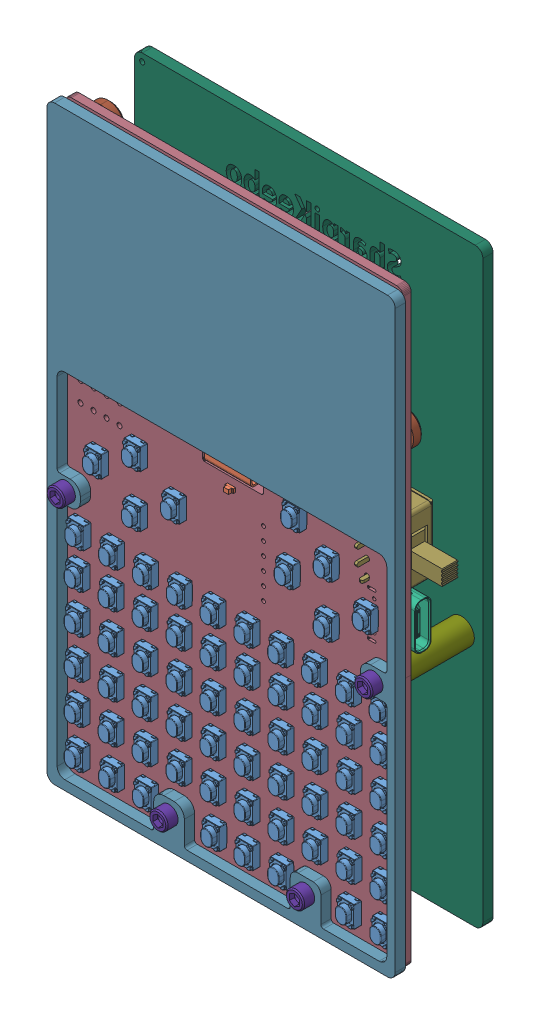
SolidWorks assembly boxingmars2024, configuration Défaut. Lengths in mm.
Overall size (72.24 115.41 21.31).
367 component instances, 20 part files, 1 mates.
Components (placement in the parent):
- pcbframe-1: pcbframe [Défaut] at (-188.8315 111.9596 -2.6) size (72.24 115.41 21.31)
  - pcbframe.STEP-1: pcbframe.STEP [Défaut] at origin size (71.24 115.32 9.7)
    - pcbframe.step.STEP-1: pcbframe.step.STEP [Défaut] at origin size (71.24 115.32 9.7)
      - SKRPABE010.step.STEP-1: SKRPABE010.step.STEP [Défaut] at (152.039 -127.29 1.65) x (0 1 0) z (1 0 0) size (4.6 2.5 3.2)
        - SOLID.step.STEP-1: SOLID.step.STEP [Défaut] at origin size (4.6 2.5 3.2)
      - SKRPABE010.step.STEP-2: SKRPABE010.step.STEP [Défaut] at (158.671 -127.29 1.65) x (0 1 0) z (1 0 0) size (4.6 2.5 3.2)
        - SOLID.step.STEP-1: SOLID.step.STEP [Défaut] at origin size (4.6 2.5 3.2)
      - SKRPABE010.step.STEP-3: SKRPABE010.step.STEP [Défaut] at (165.303 -127.29 1.65) x (0 1 0) z (1 0 0) size (4.6 2.5 3.2)
        - SOLID.step.STEP-1: SOLID.step.STEP [Défaut] at origin size (4.6 2.5 3.2)
      - SKRPABE010.step.STEP-4: SKRPABE010.step.STEP [Défaut] at (171.936 -127.29 1.65) x (0 1 0) z (1 0 0) size (4.6 2.5 3.2)
        - SOLID.step.STEP-1: SOLID.step.STEP [Défaut] at origin size (4.6 2.5 3.2)
      - SKRPABE010.step.STEP-5: SKRPABE010.step.STEP [Défaut] at (178.568 -127.29 1.65) x (0 1 0) z (1 0 0) size (4.6 2.5 3.2)
        - SOLID.step.STEP-1: SOLID.step.STEP [Défaut] at origin size (4.6 2.5 3.2)
      - SKRPABE010.step.STEP-6: SKRPABE010.step.STEP [Défaut] at (185.2 -127.29 1.65) x (0 1 0) z (1 0 0) size (4.6 2.5 3.2)
        - SOLID.step.STEP-1: SOLID.step.STEP [Défaut] at origin size (4.6 2.5 3.2)
      - SKRPABE010.step.STEP-7: SKRPABE010.step.STEP [Défaut] at (191.832 -127.29 1.65) x (0 1 0) z (1 0 0) size (4.6 2.5 3.2)
        - SOLID.step.STEP-1: SOLID.step.STEP [Défaut] at origin size (4.6 2.5 3.2)
      - SKRPABE010.step.STEP-8: SKRPABE010.step.STEP [Défaut] at (198.465 -127.29 1.65) x (0 1 0) z (1 0 0) size (4.6 2.5 3.2)
        - SOLID.step.STEP-1: SOLID.step.STEP [Défaut] at origin size (4.6 2.5 3.2)
      - SKRPABE010.step.STEP-9: SKRPABE010.step.STEP [Défaut] at (205.097 -127.29 1.65) x (0 1 0) z (1 0 0) size (4.6 2.5 3.2)
        - SOLID.step.STEP-1: SOLID.step.STEP [Défaut] at origin size (4.6 2.5 3.2)
      - SKRPABE010.step.STEP-10: SKRPABE010.step.STEP [Défaut] at (200.68 -101.255 1.65) x (0 1 0) z (1 0 0) size (4.6 2.5 3.2)
        - SOLID.step.STEP-1: SOLID.step.STEP [Défaut] at origin size (4.6 2.5 3.2)
      - SKRPABE010.step.STEP-11: SKRPABE010.step.STEP [Défaut] at (200.68 -111.415 1.65) x (0 1 0) z (1 0 0) size (4.6 2.5 3.2)
        - SOLID.step.STEP-1: SOLID.step.STEP [Défaut] at origin size (4.6 2.5 3.2)
      - SKRPABE010.step.STEP-12: SKRPABE010.step.STEP [Défaut] at (152.039 -134.91 1.65) x (0 1 0) z (1 0 0) size (4.6 2.5 3.2)
        - SOLID.step.STEP-1: SOLID.step.STEP [Défaut] at origin size (4.6 2.5 3.2)
      - SKRPABE010.step.STEP-13: SKRPABE010.step.STEP [Défaut] at (158.671 -134.91 1.65) x (0 1 0) z (1 0 0) size (4.6 2.5 3.2)
        - SOLID.step.STEP-1: SOLID.step.STEP [Défaut] at origin size (4.6 2.5 3.2)
      - SKRPABE010.step.STEP-14: SKRPABE010.step.STEP [Défaut] at (165.303 -134.91 1.65) x (0 1 0) z (1 0 0) size (4.6 2.5 3.2)
        - SOLID.step.STEP-1: SOLID.step.STEP [Défaut] at origin size (4.6 2.5 3.2)
      - SKRPABE010.step.STEP-15: SKRPABE010.step.STEP [Défaut] at (171.936 -134.91 1.65) x (0 1 0) z (1 0 0) size (4.6 2.5 3.2)
        - SOLID.step.STEP-1: SOLID.step.STEP [Défaut] at origin size (4.6 2.5 3.2)
      - SKRPABE010.step.STEP-16: SKRPABE010.step.STEP [Défaut] at (178.568 -134.91 1.65) x (0 1 0) z (1 0 0) size (4.6 2.5 3.2)
        - SOLID.step.STEP-1: SOLID.step.STEP [Défaut] at origin size (4.6 2.5 3.2)
      - SKRPABE010.step.STEP-17: SKRPABE010.step.STEP [Défaut] at (185.2 -134.91 1.65) x (0 1 0) z (1 0 0) size (4.6 2.5 3.2)
        - SOLID.step.STEP-1: SOLID.step.STEP [Défaut] at origin size (4.6 2.5 3.2)
      - SKRPABE010.step.STEP-18: SKRPABE010.step.STEP [Défaut] at (191.832 -134.91 1.65) x (0 1 0) z (1 0 0) size (4.6 2.5 3.2)
        - SOLID.step.STEP-1: SOLID.step.STEP [Défaut] at origin size (4.6 2.5 3.2)
      - SKRPABE010.step.STEP-19: SKRPABE010.step.STEP [Défaut] at (198.465 -134.91 1.65) x (0 1 0) z (1 0 0) size (4.6 2.5 3.2)
        - SOLID.step.STEP-1: SOLID.step.STEP [Défaut] at origin size (4.6 2.5 3.2)
      - SKRPABE010.step.STEP-20: SKRPABE010.step.STEP [Défaut] at (205.097 -134.91 1.65) x (0 1 0) z (1 0 0) size (4.6 2.5 3.2)
        - SOLID.step.STEP-1: SOLID.step.STEP [Défaut] at origin size (4.6 2.5 3.2)
      - SKRPABE010.step.STEP-21: SKRPABE010.step.STEP [Défaut] at (211.729 -134.91 1.65) x (0 1 0) z (1 0 0) size (4.6 2.5 3.2)
        - SOLID.step.STEP-1: SOLID.step.STEP [Défaut] at origin size (4.6 2.5 3.2)
      - SKRPABE010.step.STEP-22: SKRPABE010.step.STEP [Défaut] at (193.06 -106.335 1.65) x (0 1 0) z (1 0 0) size (4.6 2.5 3.2)
        - SOLID.step.STEP-1: SOLID.step.STEP [Défaut] at origin size (4.6 2.5 3.2)
      - SKRPABE010.step.STEP-23: SKRPABE010.step.STEP [Défaut] at (208.3 -106.335 1.65) x (0 1 0) z (1 0 0) size (4.6 2.5 3.2)
        - SOLID.step.STEP-1: SOLID.step.STEP [Défaut] at origin size (4.6 2.5 3.2)
      - SKRPABE010.step.STEP-24: SKRPABE010.step.STEP [Défaut] at (152.039 -142.53 1.65) x (0 1 0) z (1 0 0) size (4.6 2.5 3.2)
        - SOLID.step.STEP-1: SOLID.step.STEP [Défaut] at origin size (4.6 2.5 3.2)
      - SKRPABE010.step.STEP-25: SKRPABE010.step.STEP [Défaut] at (158.671 -142.53 1.65) x (0 1 0) z (1 0 0) size (4.6 2.5 3.2)
        - SOLID.step.STEP-1: SOLID.step.STEP [Défaut] at origin size (4.6 2.5 3.2)
      - SKRPABE010.step.STEP-26: SKRPABE010.step.STEP [Défaut] at (165.303 -142.53 1.65) x (0 1 0) z (1 0 0) size (4.6 2.5 3.2)
        - SOLID.step.STEP-1: SOLID.step.STEP [Défaut] at origin size (4.6 2.5 3.2)
      - SKRPABE010.step.STEP-27: SKRPABE010.step.STEP [Défaut] at (171.936 -142.53 1.65) x (0 1 0) z (1 0 0) size (4.6 2.5 3.2)
        - SOLID.step.STEP-1: SOLID.step.STEP [Défaut] at origin size (4.6 2.5 3.2)
      - SKRPABE010.step.STEP-28: SKRPABE010.step.STEP [Défaut] at (185.2 -142.53 1.65) x (0 1 0) z (1 0 0) size (4.6 2.5 3.2)
        - SOLID.step.STEP-1: SOLID.step.STEP [Défaut] at origin size (4.6 2.5 3.2)
      - SKRPABE010.step.STEP-29: SKRPABE010.step.STEP [Défaut] at (191.832 -142.53 1.65) x (0 1 0) z (1 0 0) size (4.6 2.5 3.2)
        - SOLID.step.STEP-1: SOLID.step.STEP [Défaut] at origin size (4.6 2.5 3.2)
      - SKRPABE010.step.STEP-30: SKRPABE010.step.STEP [Défaut] at (198.465 -142.53 1.65) x (0 1 0) z (1 0 0) size (4.6 2.5 3.2)
        - SOLID.step.STEP-1: SOLID.step.STEP [Défaut] at origin size (4.6 2.5 3.2)
      - SKRPABE010.step.STEP-31: SKRPABE010.step.STEP [Défaut] at (205.097 -142.53 1.65) x (0 1 0) z (1 0 0) size (4.6 2.5 3.2)
        - SOLID.step.STEP-1: SOLID.step.STEP [Défaut] at origin size (4.6 2.5 3.2)
      - SKRPABE010.step.STEP-32: SKRPABE010.step.STEP [Défaut] at (211.729 -142.53 1.65) x (0 1 0) z (1 0 0) size (4.6 2.5 3.2)
        - SOLID.step.STEP-1: SOLID.step.STEP [Défaut] at origin size (4.6 2.5 3.2)
      - SKRPABE010.step.STEP-33: SKRPABE010.step.STEP [Défaut] at (185.186 -120.178 1.65) x (0 1 0) z (1 0 0) size (4.6 2.5 3.2)
        - SOLID.step.STEP-1: SOLID.step.STEP [Défaut] at origin size (4.6 2.5 3.2)
      - SKRPABE010.step.STEP-34: SKRPABE010.step.STEP [Défaut] at (191.79 -120.178 1.65) x (0 1 0) z (1 0 0) size (4.6 2.5 3.2)
        - SOLID.step.STEP-1: SOLID.step.STEP [Défaut] at origin size (4.6 2.5 3.2)
      - SKRPABE010.step.STEP-35: SKRPABE010.step.STEP [Défaut] at (152.039 -150.15 1.65) x (0 1 0) z (1 0 0) size (4.6 2.5 3.2)
        - SOLID.step.STEP-1: SOLID.step.STEP [Défaut] at origin size (4.6 2.5 3.2)
      - SKRPABE010.step.STEP-36: SKRPABE010.step.STEP [Défaut] at (158.671 -150.15 1.65) x (0 1 0) z (1 0 0) size (4.6 2.5 3.2)
        - SOLID.step.STEP-1: SOLID.step.STEP [Défaut] at origin size (4.6 2.5 3.2)
      - SKRPABE010.step.STEP-37: SKRPABE010.step.STEP [Défaut] at (165.303 -150.15 1.65) x (0 1 0) z (1 0 0) size (4.6 2.5 3.2)
        - SOLID.step.STEP-1: SOLID.step.STEP [Défaut] at origin size (4.6 2.5 3.2)
      - SKRPABE010.step.STEP-38: SKRPABE010.step.STEP [Défaut] at (171.936 -150.15 1.65) x (0 1 0) z (1 0 0) size (4.6 2.5 3.2)
        - SOLID.step.STEP-1: SOLID.step.STEP [Défaut] at origin size (4.6 2.5 3.2)
      - SKRPABE010.step.STEP-39: SKRPABE010.step.STEP [Défaut] at (178.568 -150.15 1.65) x (0 1 0) z (1 0 0) size (4.6 2.5 3.2)
        - SOLID.step.STEP-1: SOLID.step.STEP [Défaut] at origin size (4.6 2.5 3.2)
      - SKRPABE010.step.STEP-40: SKRPABE010.step.STEP [Défaut] at (185.2 -150.15 1.65) x (0 1 0) z (1 0 0) size (4.6 2.5 3.2)
        - SOLID.step.STEP-1: SOLID.step.STEP [Défaut] at origin size (4.6 2.5 3.2)
      - SKRPABE010.step.STEP-41: SKRPABE010.step.STEP [Défaut] at (191.832 -150.15 1.65) x (0 1 0) z (1 0 0) size (4.6 2.5 3.2)
        - SOLID.step.STEP-1: SOLID.step.STEP [Défaut] at origin size (4.6 2.5 3.2)
      - SKRPABE010.step.STEP-42: SKRPABE010.step.STEP [Défaut] at (198.465 -150.15 1.65) x (0 1 0) z (1 0 0) size (4.6 2.5 3.2)
        - SOLID.step.STEP-1: SOLID.step.STEP [Défaut] at origin size (4.6 2.5 3.2)
      - SKRPABE010.step.STEP-43: SKRPABE010.step.STEP [Défaut] at (205.097 -150.15 1.65) x (0 1 0) z (1 0 0) size (4.6 2.5 3.2)
        - SOLID.step.STEP-1: SOLID.step.STEP [Défaut] at origin size (4.6 2.5 3.2)
      - SKRPABE010.step.STEP-44: SKRPABE010.step.STEP [Défaut] at (211.729 -150.15 1.65) x (0 1 0) z (1 0 0) size (4.6 2.5 3.2)
        - SOLID.step.STEP-1: SOLID.step.STEP [Défaut] at origin size (4.6 2.5 3.2)
      - SKRPABE010.step.STEP-45: SKRPABE010.step.STEP [Défaut] at (198.394 -120.178 1.65) x (0 1 0) z (1 0 0) size (4.6 2.5 3.2)
        - SOLID.step.STEP-1: SOLID.step.STEP [Défaut] at origin size (4.6 2.5 3.2)
      - SKRPABE010.step.STEP-46: SKRPABE010.step.STEP [Défaut] at (204.998 -120.178 1.65) x (0 1 0) z (1 0 0) size (4.6 2.5 3.2)
        - SOLID.step.STEP-1: SOLID.step.STEP [Défaut] at origin size (4.6 2.5 3.2)
      - SKRPABE010.step.STEP-47: SKRPABE010.step.STEP [Défaut] at (152.039 -157.77 1.65) x (0 1 0) z (1 0 0) size (4.6 2.5 3.2)
        - SOLID.step.STEP-1: SOLID.step.STEP [Défaut] at origin size (4.6 2.5 3.2)
      - SKRPABE010.step.STEP-48: SKRPABE010.step.STEP [Défaut] at (158.77 -157.77 1.65) x (0 1 0) z (1 0 0) size (4.6 2.5 3.2)
        - SOLID.step.STEP-1: SOLID.step.STEP [Défaut] at origin size (4.6 2.5 3.2)
      - SKRPABE010.step.STEP-49: SKRPABE010.step.STEP [Défaut] at (165.374 -157.77 1.65) x (0 1 0) z (1 0 0) size (4.6 2.5 3.2)
        - SOLID.step.STEP-1: SOLID.step.STEP [Défaut] at origin size (4.6 2.5 3.2)
      - SKRPABE010.step.STEP-50: SKRPABE010.step.STEP [Défaut] at (178.709 -157.77 1.65) x (0 1 0) z (1 0 0) size (4.6 2.5 3.2)
        - SOLID.step.STEP-1: SOLID.step.STEP [Défaut] at origin size (4.6 2.5 3.2)
      - SKRPABE010.step.STEP-51: SKRPABE010.step.STEP [Défaut] at (185.186 -157.77 1.65) x (0 1 0) z (1 0 0) size (4.6 2.5 3.2)
        - SOLID.step.STEP-1: SOLID.step.STEP [Défaut] at origin size (4.6 2.5 3.2)
      - SKRPABE010.step.STEP-52: SKRPABE010.step.STEP [Défaut] at (191.79 -157.77 1.65) x (0 1 0) z (1 0 0) size (4.6 2.5 3.2)
        - SOLID.step.STEP-1: SOLID.step.STEP [Défaut] at origin size (4.6 2.5 3.2)
      - SKRPABE010.step.STEP-53: SKRPABE010.step.STEP [Défaut] at (211.729 -157.77 1.65) x (0 1 0) z (1 0 0) size (4.6 2.5 3.2)
        - SOLID.step.STEP-1: SOLID.step.STEP [Défaut] at origin size (4.6 2.5 3.2)
      - SKRPABE010.step.STEP-54: SKRPABE010.step.STEP [Défaut] at (211.602 -120.178 1.65) x (0 1 0) z (1 0 0) size (4.6 2.5 3.2)
        - SOLID.step.STEP-1: SOLID.step.STEP [Défaut] at origin size (4.6 2.5 3.2)
      - SKRPABE010.step.STEP-55: SKRPABE010.step.STEP [Défaut] at (152.166 -120.178 1.65) x (0 1 0) z (1 0 0) size (4.6 2.5 3.2)
        - SOLID.step.STEP-1: SOLID.step.STEP [Défaut] at origin size (4.6 2.5 3.2)
      - SKRPABE010.step.STEP-56: SKRPABE010.step.STEP [Défaut] at (158.77 -120.178 1.65) x (0 1 0) z (1 0 0) size (4.6 2.5 3.2)
        - SOLID.step.STEP-1: SOLID.step.STEP [Défaut] at origin size (4.6 2.5 3.2)
      - SKRPABE010.step.STEP-57: SKRPABE010.step.STEP [Défaut] at (165.374 -120.178 1.65) x (0 1 0) z (1 0 0) size (4.6 2.5 3.2)
        - SOLID.step.STEP-1: SOLID.step.STEP [Défaut] at origin size (4.6 2.5 3.2)
      - SKRPABE010.step.STEP-58: SKRPABE010.step.STEP [Défaut] at (171.978 -120.178 1.65) x (0 1 0) z (1 0 0) size (4.6 2.5 3.2)
        - SOLID.step.STEP-1: SOLID.step.STEP [Défaut] at origin size (4.6 2.5 3.2)
      - SKRPABE010.step.STEP-59: SKRPABE010.step.STEP [Défaut] at (178.582 -120.178 1.65) x (0 1 0) z (1 0 0) size (4.6 2.5 3.2)
        - SOLID.step.STEP-1: SOLID.step.STEP [Défaut] at origin size (4.6 2.5 3.2)
      - SKRPABE010.step.STEP-60: SKRPABE010.step.STEP [Défaut] at (211.729 -127.29 1.65) x (0 1 0) z (1 0 0) size (4.6 2.5 3.2)
        - SOLID.step.STEP-1: SOLID.step.STEP [Défaut] at origin size (4.6 2.5 3.2)
      - SKRPABE010.step.STEP-61: SKRPABE010.step.STEP [Défaut] at (204.998 -157.77 1.65) x (0 1 0) z (1 0 0) size (4.6 2.5 3.2)
        - SOLID.step.STEP-1: SOLID.step.STEP [Défaut] at origin size (4.6 2.5 3.2)
      - SKRPABE010.step.STEP-62: SKRPABE010.step.STEP [Défaut] at (178.568 -142.53 1.65) x (0 1 0) z (1 0 0) size (4.6 2.5 3.2)
        - SOLID.step.STEP-1: SOLID.step.STEP [Défaut] at origin size (4.6 2.5 3.2)
      - SKRPABE010.step.STEP-63: SKRPABE010.step.STEP [Défaut] at (194.33 -96.048 1.65) x (0 1 0) z (1 0 0) size (4.6 2.5 3.2)
        - SOLID.step.STEP-1: SOLID.step.STEP [Défaut] at origin size (4.6 2.5 3.2)
      - SKRPABE010.step.STEP-64: SKRPABE010.step.STEP [Défaut] at (155.595 -106.335 1.65) x (0 1 0) z (1 0 0) size (4.6 2.5 3.2)
        - SOLID.step.STEP-1: SOLID.step.STEP [Défaut] at origin size (4.6 2.5 3.2)
      - SKRPABE010.step.STEP-65: SKRPABE010.step.STEP [Défaut] at (163.215 -111.415 1.65) x (0 1 0) z (1 0 0) size (4.6 2.5 3.2)
        - SOLID.step.STEP-1: SOLID.step.STEP [Défaut] at origin size (4.6 2.5 3.2)
      - SKRPABE010.step.STEP-66: SKRPABE010.step.STEP [Défaut] at (163.215 -101.255 1.65) x (0 1 0) z (1 0 0) size (4.6 2.5 3.2)
        - SOLID.step.STEP-1: SOLID.step.STEP [Défaut] at origin size (4.6 2.5 3.2)
      - SKRPABE010.step.STEP-67: SKRPABE010.step.STEP [Défaut] at (170.835 -106.335 1.65) x (0 1 0) z (1 0 0) size (4.6 2.5 3.2)
        - SOLID.step.STEP-1: SOLID.step.STEP [Défaut] at origin size (4.6 2.5 3.2)
      - LED_0603_1608Metric.step.STEP-1: LED_0603_1608Metric.step.STEP [Défaut] at (181.204 -98.4885 1.65) size (1.6 0.8 1.1)
        - SOLID-0.step.STEP-1: SOLID-0.step.STEP [Défaut] at origin size (1.6 0.8 1.1)
      - C_0603_1608Metric.step.STEP-1: C_0603_1608Metric.step.STEP [Défaut] at (185.42 -81.915 -0.05) x (0 1 0) z (0 0 -1) size (1.6 0.8 0.8)
        - SOLID-1.step.STEP-1: SOLID-1.step.STEP [Défaut] at origin size (1.6 0.8 0.8)
      - C_0603_1608Metric.step.STEP-2: C_0603_1608Metric.step.STEP [Défaut] at (181.61 -81.915 -0.05) x (0 1 0) z (0 0 -1) size (1.6 0.8 0.8)
        - SOLID-1.step.STEP-1: SOLID-1.step.STEP [Défaut] at origin size (1.6 0.8 0.8)
      - C_0603_1608Metric.step.STEP-3: C_0603_1608Metric.step.STEP [Défaut] at (179.705 -81.915 -0.05) x (0 1 0) z (0 0 -1) size (1.6 0.8 0.8)
        - SOLID-1.step.STEP-1: SOLID-1.step.STEP [Défaut] at origin size (1.6 0.8 0.8)
      - R_0603_1608Metric.step.STEP-1: R_0603_1608Metric.step.STEP [Défaut] at (199.39 -97.7265 -0.05) x (1 0 0) z (0 0 -1) size (1.6 0.8 0.45)
        - SOLID-2.step.STEP-1: SOLID-2.step.STEP [Défaut] at origin size (1.6 0.8 0.45)
      - R_0603_1608Metric.step.STEP-2: R_0603_1608Metric.step.STEP [Défaut] at (195.136 -106.236 -0.05) x (-1 0 0) z (0 0 -1) size (1.6 0.8 0.45)
        - SOLID-2.step.STEP-1: SOLID-2.step.STEP [Défaut] at origin size (1.6 0.8 0.45)
      - R_0603_1608Metric.step.STEP-3: R_0603_1608Metric.step.STEP [Défaut] at (170.284 -95.885 -0.05) x (1 0 0) z (0 0 -1) size (1.6 0.8 0.45)
        - SOLID-2.step.STEP-1: SOLID-2.step.STEP [Défaut] at origin size (1.6 0.8 0.45)
      - R_0603_1608Metric.step.STEP-4: R_0603_1608Metric.step.STEP [Défaut] at (152.34 -106.331 -0.05) x (-1 0 0) z (0 0 -1) size (1.6 0.8 0.45)
        - SOLID-2.step.STEP-1: SOLID-2.step.STEP [Défaut] at origin size (1.6 0.8 0.45)
      - R_0603_1608Metric.step.STEP-5: R_0603_1608Metric.step.STEP [Défaut] at (156.976 -112.872 -0.05) x (-1 0 0) z (0 0 -1) size (1.6 0.8 0.45)
        - SOLID-2.step.STEP-1: SOLID-2.step.STEP [Défaut] at origin size (1.6 0.8 0.45)
      - R_0603_1608Metric.step.STEP-6: R_0603_1608Metric.step.STEP [Défaut] at (156.865 -109.696 -0.05) x (-1 0 0) z (0 0 -1) size (1.6 0.8 0.45)
        - SOLID-2.step.STEP-1: SOLID-2.step.STEP [Défaut] at origin size (1.6 0.8 0.45)
      - R_0603_1608Metric.step.STEP-7: R_0603_1608Metric.step.STEP [Défaut] at (170.18 -93.98 -0.05) x (1 0 0) z (0 0 -1) size (1.6 0.8 0.45)
        - SOLID-2.step.STEP-1: SOLID-2.step.STEP [Défaut] at origin size (1.6 0.8 0.45)
      - R_0603_1608Metric.step.STEP-8: R_0603_1608Metric.step.STEP [Défaut] at (152.467 -103.283 -0.05) x (-1 0 0) z (0 0 -1) size (1.6 0.8 0.45)
        - SOLID-2.step.STEP-1: SOLID-2.step.STEP [Défaut] at origin size (1.6 0.8 0.45)
      - R_0603_1608Metric.step.STEP-9: R_0603_1608Metric.step.STEP [Défaut] at (156.722 -106.268 -0.05) x (-1 0 0) z (0 0 -1) size (1.6 0.8 0.45)
        - SOLID-2.step.STEP-1: SOLID-2.step.STEP [Défaut] at origin size (1.6 0.8 0.45)
      - R_0603_1608Metric.step.STEP-10: R_0603_1608Metric.step.STEP [Défaut] at (156.785 -103.283 -0.05) x (-1 0 0) z (0 0 -1) size (1.6 0.8 0.45)
        - SOLID-2.step.STEP-1: SOLID-2.step.STEP [Défaut] at origin size (1.6 0.8 0.45)
      - C_0603_1608Metric.step.STEP-4: C_0603_1608Metric.step.STEP [Défaut] at (174.219 -51.1556 -0.05) x (0 1 0) z (0 0 -1) size (1.6 0.8 0.8)
        - SOLID-1.step.STEP-1: SOLID-1.step.STEP [Défaut] at origin size (1.6 0.8 0.8)
      - C_0603_1608Metric.step.STEP-5: C_0603_1608Metric.step.STEP [Défaut] at (177.775 -51.1686 -0.05) x (0 1 0) z (0 0 -1) size (1.6 0.8 0.8)
        - SOLID-1.step.STEP-1: SOLID-1.step.STEP [Défaut] at origin size (1.6 0.8 0.8)
      - C_0603_1608Metric.step.STEP-6: C_0603_1608Metric.step.STEP [Défaut] at (152.756 -66.9544 -0.05) x (0 1 0) z (0 0 -1) size (1.6 0.8 0.8)
        - SOLID-1.step.STEP-1: SOLID-1.step.STEP [Défaut] at origin size (1.6 0.8 0.8)
      - C_0603_1608Metric.step.STEP-7: C_0603_1608Metric.step.STEP [Défaut] at (172.441 -51.1686 -0.05) x (0 1 0) z (0 0 -1) size (1.6 0.8 0.8)
        - SOLID-1.step.STEP-1: SOLID-1.step.STEP [Défaut] at origin size (1.6 0.8 0.8)
      - C_0603_1608Metric.step.STEP-8: C_0603_1608Metric.step.STEP [Défaut] at (175.997 -51.1686 -0.05) x (0 1 0) z (0 0 -1) size (1.6 0.8 0.8)
        - SOLID-1.step.STEP-1: SOLID-1.step.STEP [Défaut] at origin size (1.6 0.8 0.8)
      - D_SOD-323.step.STEP-1: D_SOD-323.step.STEP [Défaut] at (151.892 -127.254 -0.05) x (0 -1 0) z (0 0 -1) size (2.5 1.25 1.1)
        - SOLID-3.step.STEP-1: SOLID-3.step.STEP [Défaut] at origin size (2.5 1.25 1.1)
      - D_SOD-323.step.STEP-2: D_SOD-323.step.STEP [Défaut] at (158.496 -127.254 -0.05) x (0 -1 0) z (0 0 -1) size (2.5 1.25 1.1)
        - SOLID-3.step.STEP-1: SOLID-3.step.STEP [Défaut] at origin size (2.5 1.25 1.1)
      - D_SOD-323.step.STEP-3: D_SOD-323.step.STEP [Défaut] at (165.1 -127.254 -0.05) x (0 -1 0) z (0 0 -1) size (2.5 1.25 1.1)
        - SOLID-3.step.STEP-1: SOLID-3.step.STEP [Défaut] at origin size (2.5 1.25 1.1)
      - D_SOD-323.step.STEP-4: D_SOD-323.step.STEP [Défaut] at (171.704 -127.254 -0.05) x (0 -1 0) z (0 0 -1) size (2.5 1.25 1.1)
        - SOLID-3.step.STEP-1: SOLID-3.step.STEP [Défaut] at origin size (2.5 1.25 1.1)
      - D_SOD-323.step.STEP-5: D_SOD-323.step.STEP [Défaut] at (178.308 -127.254 -0.05) x (0 -1 0) z (0 0 -1) size (2.5 1.25 1.1)
        - SOLID-3.step.STEP-1: SOLID-3.step.STEP [Défaut] at origin size (2.5 1.25 1.1)
      - D_SOD-323.step.STEP-6: D_SOD-323.step.STEP [Défaut] at (185.166 -127.254 -0.05) x (0 -1 0) z (0 0 -1) size (2.5 1.25 1.1)
        - SOLID-3.step.STEP-1: SOLID-3.step.STEP [Défaut] at origin size (2.5 1.25 1.1)
      - D_SOD-323.step.STEP-7: D_SOD-323.step.STEP [Défaut] at (191.77 -127.254 -0.05) x (0 -1 0) z (0 0 -1) size (2.5 1.25 1.1)
        - SOLID-3.step.STEP-1: SOLID-3.step.STEP [Défaut] at origin size (2.5 1.25 1.1)
      - D_SOD-323.step.STEP-8: D_SOD-323.step.STEP [Défaut] at (198.374 -127.254 -0.05) x (0 -1 0) z (0 0 -1) size (2.5 1.25 1.1)
        - SOLID-3.step.STEP-1: SOLID-3.step.STEP [Défaut] at origin size (2.5 1.25 1.1)
      - D_SOD-323.step.STEP-9: D_SOD-323.step.STEP [Défaut] at (204.978 -127.254 -0.05) x (0 -1 0) z (0 0 -1) size (2.5 1.25 1.1)
        - SOLID-3.step.STEP-1: SOLID-3.step.STEP [Défaut] at origin size (2.5 1.25 1.1)
      - D_SOD-323.step.STEP-10: D_SOD-323.step.STEP [Défaut] at (211.582 -127.274 -0.05) x (0 -1 0) z (0 0 -1) size (2.5 1.25 1.1)
        - SOLID-3.step.STEP-1: SOLID-3.step.STEP [Défaut] at origin size (2.5 1.25 1.1)
      - D_SOD-323.step.STEP-11: D_SOD-323.step.STEP [Défaut] at (206.946 -114.18 -0.05) x (0 -1 0) z (0 0 -1) size (2.5 1.25 1.1)
        - SOLID-3.step.STEP-1: SOLID-3.step.STEP [Défaut] at origin size (2.5 1.25 1.1)
      - D_SOD-323.step.STEP-12: D_SOD-323.step.STEP [Défaut] at (202.374 -114.216 -0.05) x (0 -1 0) z (0 0 -1) size (2.5 1.25 1.1)
        - SOLID-3.step.STEP-1: SOLID-3.step.STEP [Défaut] at origin size (2.5 1.25 1.1)
      - D_SOD-323.step.STEP-13: D_SOD-323.step.STEP [Défaut] at (151.892 -134.874 -0.05) x (0 -1 0) z (0 0 -1) size (2.5 1.25 1.1)
        - SOLID-3.step.STEP-1: SOLID-3.step.STEP [Défaut] at origin size (2.5 1.25 1.1)
      - D_SOD-323.step.STEP-14: D_SOD-323.step.STEP [Défaut] at (158.496 -134.874 -0.05) x (0 -1 0) z (0 0 -1) size (2.5 1.25 1.1)
        - SOLID-3.step.STEP-1: SOLID-3.step.STEP [Défaut] at origin size (2.5 1.25 1.1)
      - D_SOD-323.step.STEP-15: D_SOD-323.step.STEP [Défaut] at (165.1 -134.874 -0.05) x (0 -1 0) z (0 0 -1) size (2.5 1.25 1.1)
        - SOLID-3.step.STEP-1: SOLID-3.step.STEP [Défaut] at origin size (2.5 1.25 1.1)
      - D_SOD-323.step.STEP-16: D_SOD-323.step.STEP [Défaut] at (171.704 -134.874 -0.05) x (0 -1 0) z (0 0 -1) size (2.5 1.25 1.1)
        - SOLID-3.step.STEP-1: SOLID-3.step.STEP [Défaut] at origin size (2.5 1.25 1.1)
      - D_SOD-323.step.STEP-17: D_SOD-323.step.STEP [Défaut] at (178.562 -134.874 -0.05) x (0 -1 0) z (0 0 -1) size (2.5 1.25 1.1)
        - SOLID-3.step.STEP-1: SOLID-3.step.STEP [Défaut] at origin size (2.5 1.25 1.1)
      - D_SOD-323.step.STEP-18: D_SOD-323.step.STEP [Défaut] at (185.166 -134.874 -0.05) x (0 -1 0) z (0 0 -1) size (2.5 1.25 1.1)
        - SOLID-3.step.STEP-1: SOLID-3.step.STEP [Défaut] at origin size (2.5 1.25 1.1)
      - D_SOD-323.step.STEP-19: D_SOD-323.step.STEP [Défaut] at (191.516 -134.874 -0.05) x (0 -1 0) z (0 0 -1) size (2.5 1.25 1.1)
        - SOLID-3.step.STEP-1: SOLID-3.step.STEP [Défaut] at origin size (2.5 1.25 1.1)
      - D_SOD-323.step.STEP-20: D_SOD-323.step.STEP [Défaut] at (198.374 -134.874 -0.05) x (0 -1 0) z (0 0 -1) size (2.5 1.25 1.1)
        - SOLID-3.step.STEP-1: SOLID-3.step.STEP [Défaut] at origin size (2.5 1.25 1.1)
      - D_SOD-323.step.STEP-21: D_SOD-323.step.STEP [Défaut] at (204.978 -134.874 -0.05) x (0 -1 0) z (0 0 -1) size (2.5 1.25 1.1)
        - SOLID-3.step.STEP-1: SOLID-3.step.STEP [Défaut] at origin size (2.5 1.25 1.1)
      - D_SOD-323.step.STEP-22: D_SOD-323.step.STEP [Défaut] at (211.582 -134.874 -0.05) x (0 -1 0) z (0 0 -1) size (2.5 1.25 1.1)
        - SOLID-3.step.STEP-1: SOLID-3.step.STEP [Défaut] at origin size (2.5 1.25 1.1)
      - D_SOD-323.step.STEP-23: D_SOD-323.step.STEP [Défaut] at (197.866 -114.18 -0.05) x (0 -1 0) z (0 0 -1) size (2.5 1.25 1.1)
        - SOLID-3.step.STEP-1: SOLID-3.step.STEP [Défaut] at origin size (2.5 1.25 1.1)
      - D_SOD-323.step.STEP-24: D_SOD-323.step.STEP [Défaut] at (192.024 -114.18 -0.05) x (0 -1 0) z (0 0 -1) size (2.5 1.25 1.1)
        - SOLID-3.step.STEP-1: SOLID-3.step.STEP [Défaut] at origin size (2.5 1.25 1.1)
      - D_SOD-323.step.STEP-25: D_SOD-323.step.STEP [Défaut] at (151.892 -142.494 -0.05) x (0 -1 0) z (0 0 -1) size (2.5 1.25 1.1)
        - SOLID-3.step.STEP-1: SOLID-3.step.STEP [Défaut] at origin size (2.5 1.25 1.1)
      - D_SOD-323.step.STEP-26: D_SOD-323.step.STEP [Défaut] at (158.496 -142.494 -0.05) x (0 -1 0) z (0 0 -1) size (2.5 1.25 1.1)
        - SOLID-3.step.STEP-1: SOLID-3.step.STEP [Défaut] at origin size (2.5 1.25 1.1)
      - D_SOD-323.step.STEP-27: D_SOD-323.step.STEP [Défaut] at (165.1 -142.494 -0.05) x (0 -1 0) z (0 0 -1) size (2.5 1.25 1.1)
        - SOLID-3.step.STEP-1: SOLID-3.step.STEP [Défaut] at origin size (2.5 1.25 1.1)
      - D_SOD-323.step.STEP-28: D_SOD-323.step.STEP [Défaut] at (171.704 -142.494 -0.05) x (0 -1 0) z (0 0 -1) size (2.5 1.25 1.1)
        - SOLID-3.step.STEP-1: SOLID-3.step.STEP [Défaut] at origin size (2.5 1.25 1.1)
      - D_SOD-323.step.STEP-29: D_SOD-323.step.STEP [Défaut] at (178.562 -142.494 -0.05) x (0 -1 0) z (0 0 -1) size (2.5 1.25 1.1)
        - SOLID-3.step.STEP-1: SOLID-3.step.STEP [Défaut] at origin size (2.5 1.25 1.1)
      - D_SOD-323.step.STEP-30: D_SOD-323.step.STEP [Défaut] at (184.912 -142.494 -0.05) x (0 -1 0) z (0 0 -1) size (2.5 1.25 1.1)
        - SOLID-3.step.STEP-1: SOLID-3.step.STEP [Défaut] at origin size (2.5 1.25 1.1)
      - D_SOD-323.step.STEP-31: D_SOD-323.step.STEP [Défaut] at (191.77 -142.494 -0.05) x (0 -1 0) z (0 0 -1) size (2.5 1.25 1.1)
        - SOLID-3.step.STEP-1: SOLID-3.step.STEP [Défaut] at origin size (2.5 1.25 1.1)
      - D_SOD-323.step.STEP-32: D_SOD-323.step.STEP [Défaut] at (198.12 -142.494 -0.05) x (0 -1 0) z (0 0 -1) size (2.5 1.25 1.1)
        - SOLID-3.step.STEP-1: SOLID-3.step.STEP [Défaut] at origin size (2.5 1.25 1.1)
      - D_SOD-323.step.STEP-33: D_SOD-323.step.STEP [Défaut] at (204.978 -142.494 -0.05) x (0 -1 0) z (0 0 -1) size (2.5 1.25 1.1)
        - SOLID-3.step.STEP-1: SOLID-3.step.STEP [Défaut] at origin size (2.5 1.25 1.1)
      - D_SOD-323.step.STEP-34: D_SOD-323.step.STEP [Défaut] at (211.582 -142.494 -0.05) x (0 -1 0) z (0 0 -1) size (2.5 1.25 1.1)
        - SOLID-3.step.STEP-1: SOLID-3.step.STEP [Défaut] at origin size (2.5 1.25 1.1)
      - D_SOD-323.step.STEP-35: D_SOD-323.step.STEP [Défaut] at (185.166 -120.142 -0.05) x (0 -1 0) z (0 0 -1) size (2.5 1.25 1.1)
        - SOLID-3.step.STEP-1: SOLID-3.step.STEP [Défaut] at origin size (2.5 1.25 1.1)
      - D_SOD-323.step.STEP-36: D_SOD-323.step.STEP [Défaut] at (191.77 -120.142 -0.05) x (0 -1 0) z (0 0 -1) size (2.5 1.25 1.1)
        - SOLID-3.step.STEP-1: SOLID-3.step.STEP [Défaut] at origin size (2.5 1.25 1.1)
      - D_SOD-323.step.STEP-37: D_SOD-323.step.STEP [Défaut] at (151.892 -150.114 -0.05) x (0 -1 0) z (0 0 -1) size (2.5 1.25 1.1)
        - SOLID-3.step.STEP-1: SOLID-3.step.STEP [Défaut] at origin size (2.5 1.25 1.1)
      - D_SOD-323.step.STEP-38: D_SOD-323.step.STEP [Défaut] at (158.75 -150.114 -0.05) x (0 -1 0) z (0 0 -1) size (2.5 1.25 1.1)
        - SOLID-3.step.STEP-1: SOLID-3.step.STEP [Défaut] at origin size (2.5 1.25 1.1)
      - D_SOD-323.step.STEP-39: D_SOD-323.step.STEP [Défaut] at (165.1 -150.114 -0.05) x (0 -1 0) z (0 0 -1) size (2.5 1.25 1.1)
        - SOLID-3.step.STEP-1: SOLID-3.step.STEP [Défaut] at origin size (2.5 1.25 1.1)
      - D_SOD-323.step.STEP-40: D_SOD-323.step.STEP [Défaut] at (171.958 -150.114 -0.05) x (0 -1 0) z (0 0 -1) size (2.5 1.25 1.1)
        - SOLID-3.step.STEP-1: SOLID-3.step.STEP [Défaut] at origin size (2.5 1.25 1.1)
      - D_SOD-323.step.STEP-41: D_SOD-323.step.STEP [Défaut] at (178.308 -150.114 -0.05) x (0 -1 0) z (0 0 -1) size (2.5 1.25 1.1)
        - SOLID-3.step.STEP-1: SOLID-3.step.STEP [Défaut] at origin size (2.5 1.25 1.1)
      - D_SOD-323.step.STEP-42: D_SOD-323.step.STEP [Défaut] at (185.166 -150.114 -0.05) x (0 -1 0) z (0 0 -1) size (2.5 1.25 1.1)
        - SOLID-3.step.STEP-1: SOLID-3.step.STEP [Défaut] at origin size (2.5 1.25 1.1)
      - D_SOD-323.step.STEP-43: D_SOD-323.step.STEP [Défaut] at (191.77 -150.114 -0.05) x (0 -1 0) z (0 0 -1) size (2.5 1.25 1.1)
        - SOLID-3.step.STEP-1: SOLID-3.step.STEP [Défaut] at origin size (2.5 1.25 1.1)
      - D_SOD-323.step.STEP-44: D_SOD-323.step.STEP [Défaut] at (198.374 -150.114 -0.05) x (0 -1 0) z (0 0 -1) size (2.5 1.25 1.1)
        - SOLID-3.step.STEP-1: SOLID-3.step.STEP [Défaut] at origin size (2.5 1.25 1.1)
      - D_SOD-323.step.STEP-45: D_SOD-323.step.STEP [Défaut] at (204.978 -150.114 -0.05) x (0 -1 0) z (0 0 -1) size (2.5 1.25 1.1)
        - SOLID-3.step.STEP-1: SOLID-3.step.STEP [Défaut] at origin size (2.5 1.25 1.1)
      - D_SOD-323.step.STEP-46: D_SOD-323.step.STEP [Défaut] at (211.836 -150.114 -0.05) x (0 -1 0) z (0 0 -1) size (2.5 1.25 1.1)
        - SOLID-3.step.STEP-1: SOLID-3.step.STEP [Défaut] at origin size (2.5 1.25 1.1)
      - D_SOD-323.step.STEP-47: D_SOD-323.step.STEP [Défaut] at (198.374 -120.142 -0.05) x (0 -1 0) z (0 0 -1) size (2.5 1.25 1.1)
        - SOLID-3.step.STEP-1: SOLID-3.step.STEP [Défaut] at origin size (2.5 1.25 1.1)
      - D_SOD-323.step.STEP-48: D_SOD-323.step.STEP [Défaut] at (204.978 -120.142 -0.05) x (0 -1 0) z (0 0 -1) size (2.5 1.25 1.1)
        - SOLID-3.step.STEP-1: SOLID-3.step.STEP [Défaut] at origin size (2.5 1.25 1.1)
      - D_SOD-323.step.STEP-49: D_SOD-323.step.STEP [Défaut] at (151.892 -157.734 -0.05) x (0 -1 0) z (0 0 -1) size (2.5 1.25 1.1)
        - SOLID-3.step.STEP-1: SOLID-3.step.STEP [Défaut] at origin size (2.5 1.25 1.1)
      - D_SOD-323.step.STEP-50: D_SOD-323.step.STEP [Défaut] at (158.75 -157.734 -0.05) x (0 -1 0) z (0 0 -1) size (2.5 1.25 1.1)
        - SOLID-3.step.STEP-1: SOLID-3.step.STEP [Défaut] at origin size (2.5 1.25 1.1)
      - D_SOD-323.step.STEP-51: D_SOD-323.step.STEP [Défaut] at (165.1 -157.734 -0.05) x (0 -1 0) z (0 0 -1) size (2.5 1.25 1.1)
        - SOLID-3.step.STEP-1: SOLID-3.step.STEP [Défaut] at origin size (2.5 1.25 1.1)
      - D_SOD-323.step.STEP-52: D_SOD-323.step.STEP [Défaut] at (178.562 -157.734 -0.05) x (0 -1 0) z (0 0 -1) size (2.5 1.25 1.1)
        - SOLID-3.step.STEP-1: SOLID-3.step.STEP [Défaut] at origin size (2.5 1.25 1.1)
      - D_SOD-323.step.STEP-53: D_SOD-323.step.STEP [Défaut] at (204.978 -157.734 -0.05) x (0 -1 0) z (0 0 -1) size (2.5 1.25 1.1)
        - SOLID-3.step.STEP-1: SOLID-3.step.STEP [Défaut] at origin size (2.5 1.25 1.1)
      - D_SOD-323.step.STEP-54: D_SOD-323.step.STEP [Défaut] at (211.582 -157.734 -0.05) x (0 -1 0) z (0 0 -1) size (2.5 1.25 1.1)
        - SOLID-3.step.STEP-1: SOLID-3.step.STEP [Défaut] at origin size (2.5 1.25 1.1)
      - D_SOD-323.step.STEP-55: D_SOD-323.step.STEP [Défaut] at (211.582 -120.142 -0.05) x (0 -1 0) z (0 0 -1) size (2.5 1.25 1.1)
        - SOLID-3.step.STEP-1: SOLID-3.step.STEP [Défaut] at origin size (2.5 1.25 1.1)
      - D_SOD-323.step.STEP-56: D_SOD-323.step.STEP [Défaut] at (152.146 -120.142 -0.05) x (0 -1 0) z (0 0 -1) size (2.5 1.25 1.1)
        - SOLID-3.step.STEP-1: SOLID-3.step.STEP [Défaut] at origin size (2.5 1.25 1.1)
      - D_SOD-323.step.STEP-57: D_SOD-323.step.STEP [Défaut] at (158.75 -120.142 -0.05) x (0 -1 0) z (0 0 -1) size (2.5 1.25 1.1)
        - SOLID-3.step.STEP-1: SOLID-3.step.STEP [Défaut] at origin size (2.5 1.25 1.1)
      - D_SOD-323.step.STEP-58: D_SOD-323.step.STEP [Défaut] at (165.354 -120.142 -0.05) x (0 -1 0) z (0 0 -1) size (2.5 1.25 1.1)
        - SOLID-3.step.STEP-1: SOLID-3.step.STEP [Défaut] at origin size (2.5 1.25 1.1)
      - D_SOD-323.step.STEP-59: D_SOD-323.step.STEP [Défaut] at (171.958 -120.142 -0.05) x (0 -1 0) z (0 0 -1) size (2.5 1.25 1.1)
        - SOLID-3.step.STEP-1: SOLID-3.step.STEP [Défaut] at origin size (2.5 1.25 1.1)
      - D_SOD-323.step.STEP-60: D_SOD-323.step.STEP [Défaut] at (178.562 -120.142 -0.05) x (0 -1 0) z (0 0 -1) size (2.5 1.25 1.1)
        - SOLID-3.step.STEP-1: SOLID-3.step.STEP [Défaut] at origin size (2.5 1.25 1.1)
      - USB Type C Port (SMD Type).step.STEP-1: USB Type C Port (SMD Type).step.STEP [Défaut] at (208.07 -106.3244 -1.55) x (0 -1 0) z (0 0 1) size (8.94 7.9 4.2)
        - COMPOUND.step.STEP-1: COMPOUND.step.STEP [Défaut] at origin size (8.94 7.9 4.2)
      - R_0603_1608Metric.step.STEP-11: R_0603_1608Metric.step.STEP [Défaut] at (183.553 -57.0992 -0.05) x (1 0 0) z (0 0 -1) size (1.6 0.8 0.45)
        - SOLID-2.step.STEP-1: SOLID-2.step.STEP [Défaut] at origin size (1.6 0.8 0.45)
      - R_0603_1608Metric.step.STEP-12: R_0603_1608Metric.step.STEP [Défaut] at (183.553 -60.1472 -0.05) x (-1 0 0) z (0 0 -1) size (1.6 0.8 0.45)
        - SOLID-2.step.STEP-1: SOLID-2.step.STEP [Défaut] at origin size (1.6 0.8 0.45)
      - R_0603_1608Metric.step.STEP-13: R_0603_1608Metric.step.STEP [Défaut] at (203.797 -102.26 -0.05) x (1 0 0) z (0 0 -1) size (1.6 0.8 0.45)
        - SOLID-2.step.STEP-1: SOLID-2.step.STEP [Défaut] at origin size (1.6 0.8 0.45)
      - R_0603_1608Metric.step.STEP-14: R_0603_1608Metric.step.STEP [Défaut] at (203.796 -103.911 -0.05) x (-1 0 0) z (0 0 -1) size (1.6 0.8 0.45)
        - SOLID-2.step.STEP-1: SOLID-2.step.STEP [Défaut] at origin size (1.6 0.8 0.45)
      - R_0603_1608Metric.step.STEP-15: R_0603_1608Metric.step.STEP [Défaut] at (203.772 -107.886 -0.05) x (1 0 0) z (0 0 -1) size (1.6 0.8 0.45)
        - SOLID-2.step.STEP-1: SOLID-2.step.STEP [Défaut] at origin size (1.6 0.8 0.45)
      - R_0603_1608Metric.step.STEP-16: R_0603_1608Metric.step.STEP [Défaut] at (195.136 -102.044 -0.05) x (-1 0 0) z (0 0 -1) size (1.6 0.8 0.45)
        - SOLID-2.step.STEP-1: SOLID-2.step.STEP [Défaut] at origin size (1.6 0.8 0.45)
      - SW_SPST_B3U-1000P.step.STEP-1: SW_SPST_B3U-1000P.step.STEP [Défaut] at (182.653 -54.102 -0.05) x (-1 0 0) z (0 0 -1) size (4 2.5 1.59)
        - SOLID-4.step.STEP-1: SOLID-4.step.STEP [Défaut] at origin size (4 2.5 1.59)
      - JST-S2B-PH-SM4-TB.step.STEP-1: JST-S2B-PH-SM4-TB.step.STEP [Défaut] at (153.575 -88.09 -0.05) x (0 1 0) z (0 0 -1) size (7.9 8.61 5.61)
        - COMPOUND-5.step.STEP-1: COMPOUND-5.step.STEP [Défaut] at origin size (7.9 8.61 5.61)
      - ATMEGA32U4-MU.step.STEP-1: ATMEGA32U4-MU.step.STEP [Défaut] at (161.734 -59.8805 -0.05) x (0.707107 0.707107 0) z (-0.707107 0.707107 0) size (7 1 7)
        - COMPOUND-6.step.STEP-1: COMPOUND-6.step.STEP [Défaut] at origin size (7 1 7)
      - C_0603_1608Metric.step.STEP-9: C_0603_1608Metric.step.STEP [Défaut] at (209.36 -68.6435 -0.05) x (0 -1 0) z (0 0 -1) size (1.6 0.8 0.8)
        - SOLID-1.step.STEP-1: SOLID-1.step.STEP [Défaut] at origin size (1.6 0.8 0.8)
      - R_0603_1608Metric.step.STEP-17: R_0603_1608Metric.step.STEP [Défaut] at (199.136 -68.326 -0.05) x (1 0 0) z (0 0 -1) size (1.6 0.8 0.45)
        - SOLID-2.step.STEP-1: SOLID-2.step.STEP [Défaut] at origin size (1.6 0.8 0.45)
      - R_0603_1608Metric.step.STEP-18: R_0603_1608Metric.step.STEP [Défaut] at (176.34 -58.674 -0.05) x (1 0 0) z (0 0 -1) size (1.6 0.8 0.45)
        - SOLID-2.step.STEP-1: SOLID-2.step.STEP [Défaut] at origin size (1.6 0.8 0.45)
      - R_0603_1608Metric.step.STEP-19: R_0603_1608Metric.step.STEP [Défaut] at (176.34 -60.325 -0.05) x (1 0 0) z (0 0 -1) size (1.6 0.8 0.45)
        - SOLID-2.step.STEP-1: SOLID-2.step.STEP [Défaut] at origin size (1.6 0.8 0.45)
      - C_0603_1608Metric.step.STEP-10: C_0603_1608Metric.step.STEP [Défaut] at (187.402 -57.0865 -0.05) x (1 0 0) z (0 0 -1) size (1.6 0.8 0.8)
        - SOLID-1.step.STEP-1: SOLID-1.step.STEP [Défaut] at origin size (1.6 0.8 0.8)
      - C_0603_1608Metric.step.STEP-11: C_0603_1608Metric.step.STEP [Défaut] at (187.402 -58.928 -0.05) x (1 0 0) z (0 0 -1) size (1.6 0.8 0.8)
        - SOLID-1.step.STEP-1: SOLID-1.step.STEP [Défaut] at origin size (1.6 0.8 0.8)
      - R_0603_1608Metric.step.STEP-20: R_0603_1608Metric.step.STEP [Défaut] at (170.284 -97.663 -0.05) x (1 0 0) z (0 0 -1) size (1.6 0.8 0.45)
        - SOLID-2.step.STEP-1: SOLID-2.step.STEP [Défaut] at origin size (1.6 0.8 0.45)
      - R_0603_1608Metric.step.STEP-21: R_0603_1608Metric.step.STEP [Défaut] at (168.275 -88.0745 -0.05) x (-1 0 0) z (0 0 -1) size (1.6 0.8 0.45)
        - SOLID-2.step.STEP-1: SOLID-2.step.STEP [Défaut] at origin size (1.6 0.8 0.45)
      - 16mhzcrystal.step.STEP-1: 16mhzcrystal.step.STEP [Défaut] at (156.4549 -55.7489 -0.05) x (0.707107 -0.707107 0) z (0 0 -1) size (1.3 3.2 1)
        - SOLID-7.step.STEP-1: SOLID-7.step.STEP [Défaut] at origin size (1.3 3.2 1)
      - SMTSO-M3-2.step.STEP-1: SMTSO-M3-2.step.STEP [Défaut] at (152.49 -75.74 -0.05) x (1 0 0) z (0 1 0) size (6.3 3.37 6.3)
        - SOLID-8.step.STEP-1: SOLID-8.step.STEP [Défaut] at origin size (6.3 3.37 6.3)
      - SMTSO-M3-2.step.STEP-2: SMTSO-M3-2.step.STEP [Défaut] at (152.52 -52.75 -0.05) x (1 0 0) z (0 1 0) size (6.3 3.37 6.3)
        - SOLID-8.step.STEP-1: SOLID-8.step.STEP [Défaut] at origin size (6.3 3.37 6.3)
      - SMTSO-M3-2.step.STEP-3: SMTSO-M3-2.step.STEP [Défaut] at (210.52 -75.73 -0.05) x (1 0 0) z (0 1 0) size (6.3 3.37 6.3)
        - SOLID-8.step.STEP-1: SOLID-8.step.STEP [Défaut] at origin size (6.3 3.37 6.3)
      - SW_SPST_B3U-1000P.step.STEP-2: SW_SPST_B3U-1000P.step.STEP [Défaut] at (204.343 -68.2625 -0.05) x (-1 0 0) z (0 0 -1) size (4 2.5 1.59)
        - SOLID-4.step.STEP-1: SOLID-4.step.STEP [Défaut] at origin size (4 2.5 1.59)
      - SS12F23.step.STEP-1: SS12F23.step.STEP [Défaut] at (213.33 -94.47 -0.05) x (0 -1 0) z (1 0 0) size (13 9.1 12.9)
        - COMPOUND-9.step.STEP-1: COMPOUND-9.step.STEP [Défaut] at origin size (13 9.1 12.9)
      - R_0603_1608Metric.step.STEP-22: R_0603_1608Metric.step.STEP [Défaut] at (164.084 -92.456 -0.05) x (1 0 0) z (0 0 -1) size (1.6 0.8 0.45)
        - SOLID-2.step.STEP-1: SOLID-2.step.STEP [Défaut] at origin size (1.6 0.8 0.45)
      - R_0603_1608Metric.step.STEP-23: R_0603_1608Metric.step.STEP [Défaut] at (164.4904 -82.2452 -0.05) x (-1 0 0) z (0 0 -1) size (1.6 0.8 0.45)
        - SOLID-2.step.STEP-1: SOLID-2.step.STEP [Défaut] at origin size (1.6 0.8 0.45)
      - R_0603_1608Metric.step.STEP-24: R_0603_1608Metric.step.STEP [Défaut] at (164.084 -90.424 -0.05) x (-1 0 0) z (0 0 -1) size (1.6 0.8 0.45)
        - SOLID-2.step.STEP-1: SOLID-2.step.STEP [Défaut] at origin size (1.6 0.8 0.45)
      - R_0603_1608Metric.step.STEP-25: R_0603_1608Metric.step.STEP [Défaut] at (164.1875 -88.392 -0.05) x (-1 0 0) z (0 0 -1) size (1.6 0.8 0.45)
        - SOLID-2.step.STEP-1: SOLID-2.step.STEP [Défaut] at origin size (1.6 0.8 0.45)
      - MemoryBrakout PCB.step.STEP-1: MemoryBrakout PCB.step.STEP [Défaut] at origin size (66.04 115.32 1.6)
  - coque-dessus-1: coque-dessus [Défaut] at (0 0 2.1232) size (68.03 115.32 2)
  - cpoqueinferieure-1: cpoqueinferieure [Défaut] at (0 0 -15) size (68.03 115.32 2)
  - spacer-1: spacer [Défaut] at (151.384 -112.776 -13) size (5 5 13)
  - spacer-2: spacer [Défaut] at (171.45 -157.48 -13) size (5 5 13)
  - spacer-3: spacer [Défaut] at (211.455 -114.935 -13) size (5 5 13)
  - spacer-4: spacer [Défaut] at (198.12 -157.48 -13) size (5 5 13)
  - socket head cap screw_ai-2: socket head cap screw_ai [HX-SHCS 0.086-64x0.625x0.625-N] at (151.384 -112.776 6.3076) x (0 0 -1) z (1 0 0) size (18.06 3.56 3.56)
  - socket head cap screw_ai-3: socket head cap screw_ai [HX-SHCS 0.086-64x0.625x0.625-N] at (171.45 -157.48 6.3076) x (0 0 -1) z (1 0 0) size (18.06 3.56 3.56)
  - socket head cap screw_ai-4: socket head cap screw_ai [HX-SHCS 0.086-64x0.625x0.625-N] at (211.455 -114.935 6.3076) x (0 0 -1) z (1 0 0) size (18.06 3.56 3.56)
  - socket head cap screw_ai-5: socket head cap screw_ai [HX-SHCS 0.086-64x0.625x0.625-N] at (198.12 -157.48 6.3076) x (0 0 -1) z (1 0 0) size (18.06 3.56 3.56)
  - LS027B7DH01 LCD-2: LS027B7DH01 LCD [Défaut] at (212.8905 -92.5568 2.41) x (-1 0 0) z (0 0 -1) size (62.8 45.97 3.94)
    - LS027B7DH01 LCD.stp-1: LS027B7DH01 LCD.stp [Défaut] at origin size (62.8 45.97 3.94)
      - eBom-prt0.stp-1: eBom-prt0.stp [Défaut] at origin size (62.8 42.82 1.64)
      - eBom-prt1.stp-1: eBom-prt1.stp [Défaut] at (2 5.54 -0.835) size (58.8 35.28 0.01)
      - eBom-prt2.stp-1: eBom-prt2.stp [Défaut] at (31.4 -0.8 -0.15) x (0 -1 0) z (1 0 0) size (5.35 3.4 9)
Mates (geometry in assembly coordinates):
- Coïncidente4: coincident anti-aligned: plane of topcover-1 through (-38.2415 -55.6604 -1) normal (0 0 -1); plane of pcbframe-1/pcbframe.STEP-1/pcbframe.step.STEP-1/MemoryBrakout PCB.step.STEP-1 through (-7.2215 6.0065 -1) normal (0 0 1)
